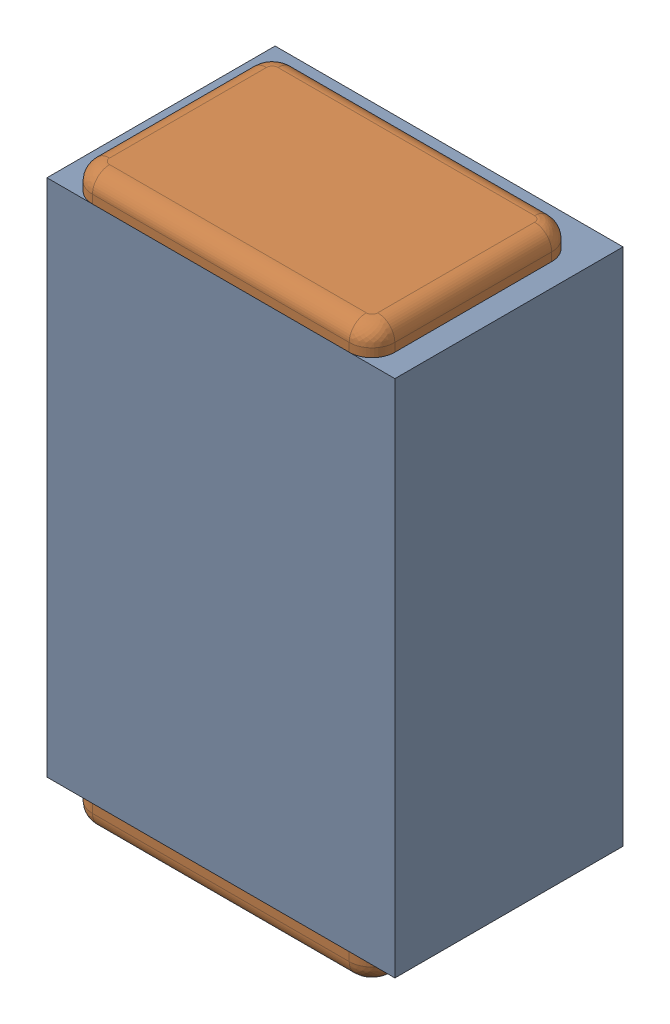
SolidWorks assembly C44, configuration Default. Lengths in mm.
Overall size (0.61 1 0.4).
3 component instances, 2 part files, 0 mates.
Components (placement in the parent):
- 1088881848-1: 1088881848 [Default] at (14.875 5.6 -2.044) size (0.61 0.91 0.4)
  - Extruded-1-1: Extruded-1 [Default] at origin size (0.61 0.91 0.4)
- C0402-1: C0402 [Default] at (14.8749 5.5999 -1.644) x (0 -1 0) z (1 0 0) size (1 0.36 0.54)
